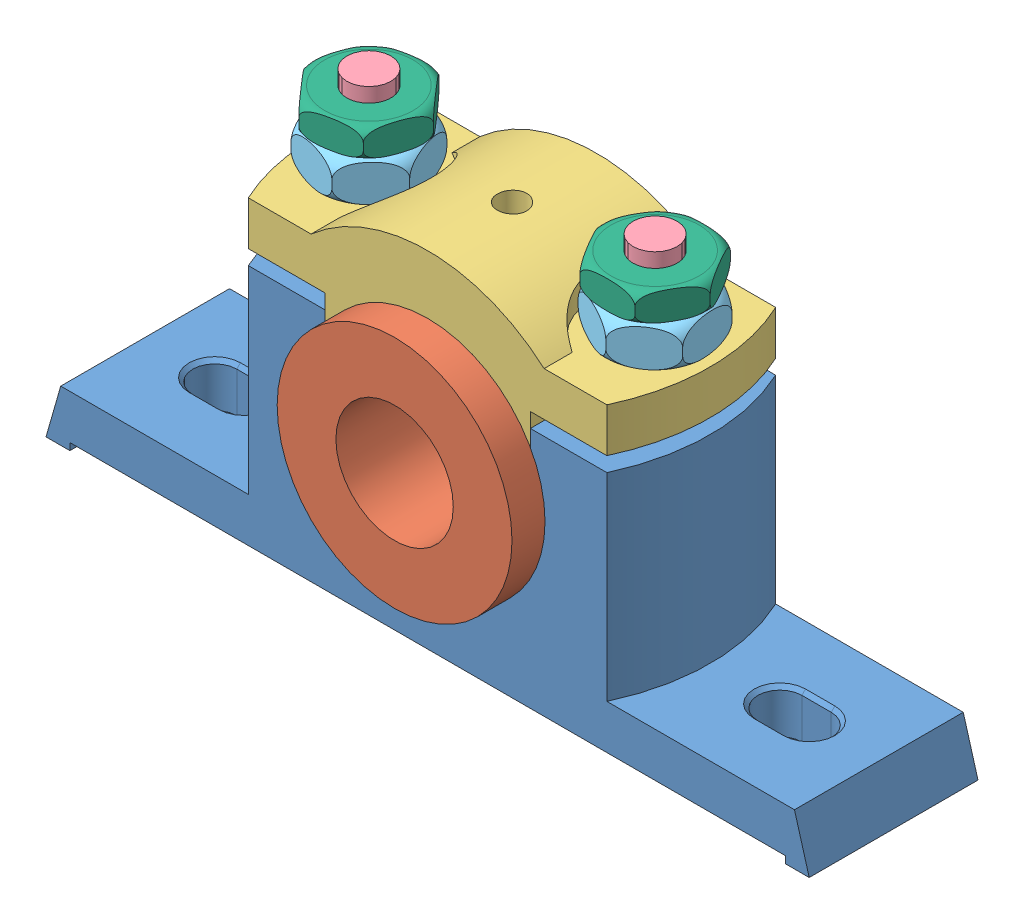
SolidWorks assembly Plummer Block Assembly, configuration Default. Lengths in mm.
Overall size (208 107.92 64).
9 component instances, 6 part files, 18 mates.
Components (placement in the parent):
- Casting-1: Casting [Default] at (91.9288 77.9097 159.3442) size (208 68 46)
- Brasses-1: Brasses [Default] at (91.9288 111.9097 168.3588) x (-1 0 0) z (0 0 1) size (64 64 64)
- Cap-2: Cap [Default] at (91.9288 111.9097 159.3442) size (108 40 46)
- Bolt-1: Bolt [Default] at (130.9288 75.8273 159.3442) x (0.015666 0 -0.999877) z (0.999877 0 0.015666) size (24 104 24)
- Bolt-2: Bolt [Default] at (52.9288 75.8273 159.3442) x (0.002071 0 -0.999998) z (0.999998 0 0.002071) size (24 104 24)
- Nut-1: Nut [Default] at (130.9288 153.9097 159.3442) x (0.811516 0 -0.584331) z (0.584331 0 0.811516) size (31.65 12 27.62)
- Nut-2: Nut [Default] at (52.9288 153.9097 159.3442) x (0.686855 0 -0.726795) z (0.726795 0 0.686855) size (31.65 12 27.62)
- Lock Nut-2: Lock Nut [Default] at (130.9288 163.9097 159.3442) size (31.52 9.12 27.5)
- Lock Nut-3: Lock Nut [Default] at (52.9288 163.9097 159.3442) x (0.982082 0 -0.188455) z (0.188455 0 0.982082) size (31.52 9.12 27.5)
Mates (geometry in assembly coordinates):
- Concentric1: concentric anti-aligned: cylinder of Casting-1 through (91.9288 111.9097 182.3442) axis (0 0 -1) radius 24; cylinder of Brasses-1 through (91.9288 111.9097 168.3588) axis (0 0 1) radius 16
- Parallel1: parallel aligned: face of Casting-1; cylinder of Brasses-1 through (91.9288 143.9107 159.3442) axis (0 -1 0) radius 4
- Coincident3: coincident anti-aligned: plane of Casting-1 through (91.9288 77.9097 182.3442) normal (0 0 1); plane of Brasses-1 through (91.9288 79.9097 182.3442) normal (0 0 -1)
- Concentric2: concentric anti-aligned: cylinder of Brasses-1 through (91.9288 143.9097 159.3442) axis (0 -1 0) radius 3; cylinder of Cap-2 through (91.9288 143.9097 159.3442) axis (0 1 0) radius 4
- Concentric3: concentric anti-aligned: cylinder of Casting-1 through (130.9288 75.8273 159.3442) axis (0 -1 0) radius 6; cylinder of Cap-2 through (130.9288 147.9097 159.3442) axis (0 1 0) radius 6
- Concentric4: concentric anti-aligned: cylinder of Brasses-1 through (91.9288 111.9097 168.3588) axis (0 0 1) radius 22; cylinder of Cap-2 through (91.9288 111.9097 182.3442) axis (0 0 -1) radius 24
- Concentric5: concentric aligned: cylinder of Casting-1 through (130.9288 75.8273 159.3442) axis (0 -1 0) radius 6; cylinder of Bolt-1 through (130.9288 171.8273 159.3442) axis (0 -1 0) radius 6
- Coincident4: coincident anti-aligned: plane of Casting-1 through (91.9288 75.8273 159.3442) normal (0 -1 0); plane of Bolt-1 through (130.9288 75.8273 159.3442) normal (0 1 0)
- Coincident5: coincident anti-aligned: plane of Casting-1 through (91.9288 75.8273 159.3442) normal (0 -1 0); plane of Bolt-2 through (52.9288 75.8273 159.3442) normal (0 1 0)
- Concentric6: concentric aligned: circle of Casting-1; cylinder of Bolt-2 through (52.9288 171.8273 159.3442) axis (0 -1 0) radius 6
- Concentric7: concentric anti-aligned: cylinder of Bolt-1 through (130.9288 171.8273 159.3442) axis (0 -1 0) radius 6; circle of Nut-1
- Coincident8: coincident anti-aligned: plane of Cap-2 through (91.9288 147.9097 159.3442) normal (0 1 0); plane of Nut-1 through (130.9288 147.9097 159.3442) normal (0 -1 0)
- Coincident9: coincident anti-aligned: plane of Cap-2 through (91.9288 147.9097 159.3442) normal (0 1 0); plane of Nut-2 through (52.9288 147.9097 159.3442) normal (0 -1 0)
- Concentric8: concentric anti-aligned: cylinder of Bolt-2 through (52.9288 171.8273 159.3442) axis (0 -1 0) radius 6; circle of Nut-2
- Concentric12: concentric aligned: cylinder of Bolt-1 through (130.9288 171.8273 159.3442) axis (0 -1 0) radius 6; cylinder of Lock Nut-2 through (130.9288 167.9097 159.3442) axis (0 -1 0) radius 6
- Coincident17: coincident anti-aligned: plane of Nut-1 through (130.9288 159.9097 159.3442) normal (0 1 0); plane of Lock Nut-2 through (130.9288 159.9097 159.3442) normal (0 -1 0)
- Coincident18: coincident anti-aligned: plane of Nut-1 through (130.9288 159.9097 159.3442) normal (0 1 0); plane of Lock Nut-3 through (52.9288 159.9097 159.3442) normal (0 -1 0)
- Concentric13: concentric aligned: cylinder of Bolt-2 through (52.9288 171.8273 159.3442) axis (0 -1 0) radius 6; cylinder of Lock Nut-3 through (52.9288 167.9097 159.3442) axis (0 -1 0) radius 6
